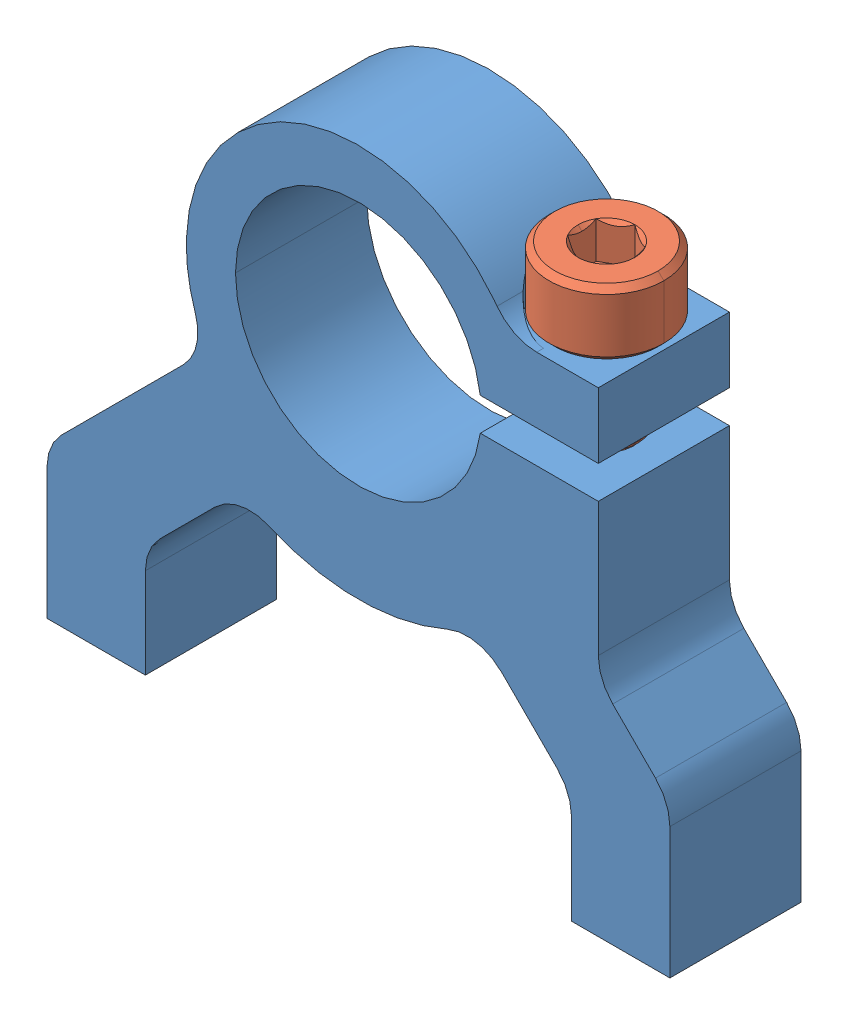
SolidWorks assembly 1-Side, 2-Post Clamping Mount (15mm Bore)1400-0032-0015, configuration Default. Lengths in mm.
Overall size (38 34.5 8).
2 component instances, 2 part files, 0 mates.
Components (placement in the parent):
- 1400-0032-0015.STEP-1: 1400-0032-0015.STEP [Default] at (-21.2886 5.2238 8.355) size (38 34.5 8)
- 2800-0004-0010_90128A207.STEP-1: 2800-0004-0010_90128A207.STEP [Default] at (-10.1556 0.2238 12.355) x (1 0 0) z (0 -1 0) size (7 7 14.01)
